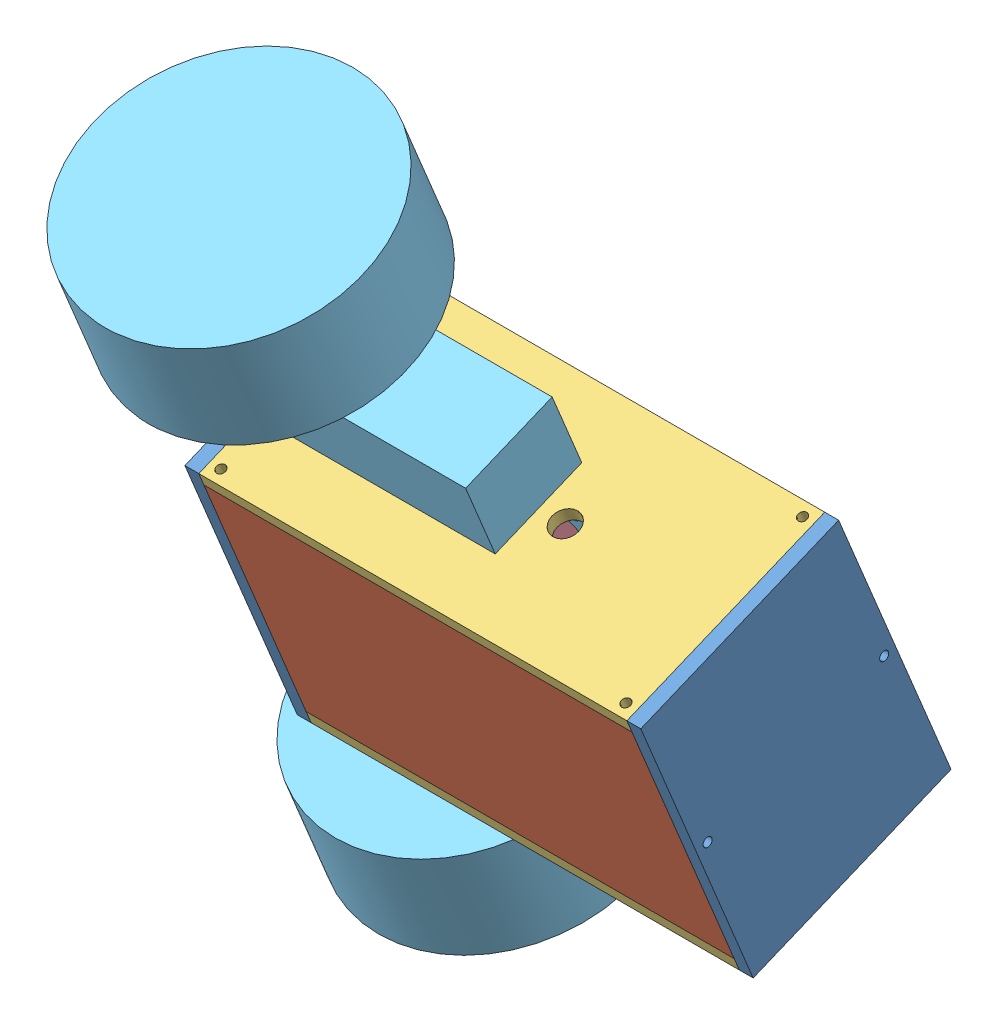
SolidWorks assembly Segway Assembly, configuration Default. Lengths in mm.
Overall size (133.86 181.3 123.57).
42 component instances, 24 part files, 24 mates.
Components (placement in the parent):
- Segway_Back-1: Segway_Back [Default] at (11.9402 18.0939 83.0712)
- Lid_Segway-3: Lid_Segway [Default] at (99.0068 121.3431 157.281) x (0 0.381849 -0.924225) z (-1 0 0) size (50.8 69.85 3.3)
- Lid_Segway-4: Lid_Segway [Default] at (203.9088 121.3431 157.281) x (0 0.381849 -0.924225) z (-1 0 0) size (50.8 69.85 3.3)
- Segway_Front-2: Segway_Front [Default] at (141.2112 46.7187 228.7497) x (1 0 0) z (0 0.924225 0.381849) size (101.6 3.17 63.5)
- Segway_side-3: Segway_side [Default] at (164.4936 84.3919 249.772) x (0 -0.381849 0.924225) z (0 0.924225 0.381849) size (50.8 101.6 3.17)
- Segway_side-4: Segway_side [Default] at (164.4936 22.7693 224.3122) x (0 -0.381849 0.924225) z (0 0.924225 0.381849) size (50.8 101.6 3.17)
- Segway_Back2-2: Segway_Back2 [Default] at (158.4024 66.1167 181.7991) x (-1 0 0) z (0 0.924225 0.381849) size (101.6 3.17 63.5)
- Final-1: Final [Predeterminado] at (194.5108 99.8085 199.1543) x (-1 0 0) z (0 0.924225 0.381849) size (74.75 15.43 53.34)
  - PCB_Final-1: PCB_Final [Default] at origin size (68.58 2 53.34)
  - Header Vertical 2.54mm Pitch2-1: Header Vertical 2.54mm Pitch2 [Header 6 Way] at (62.2731 2 -29.1415) size (5.08 8.88 7.62)
  - IC DIP 28-1: IC DIP 28 [Default] at (51.4233 4.3498 -16.4837) x (0 0.005002 0.999987) z (-1 0 0) size (7.87 6.22 35.94)
  - User Library-QFN32 (FTDI)-1: User Library-QFN32 (FTDI) [Default] at (19.2089 2.05 -38.1588) x (-1 0 0) z (0 1 0) size (5 5 0.85)
    - User Library-QFN32 (FTDI)_Anschl_X_FCsse_1-1: User Library-QFN32 (FTDI)_Anschl_X_FCsse_1 [Default] x (0 -1 0) z (0 0 1) size (5 5 0.2)
    - User Library-QFN32 (FTDI)_K_X_F6rper_1-1: User Library-QFN32 (FTDI)_K_X_F6rper_1 [Default] at origin size (5 5 0.8)
    - User Library-QFN32 (FTDI)_Beschriftung_1-1: User Library-QFN32 (FTDI)_Beschriftung_1 [Default] at origin size (0.51 0.51 0.05)
  - User Library-67068-0000-molex-1: User Library-67068-0000-molex [Default] at (-6.1546 2 -38.0545) x (0.002421 0 0.999997) z (-0.999997 0 0.002421) size (14.9 15.43 17)
  - User Library-dc range - dc connector[4840_2201]-1: User Library-dc range - dc connector[4840_2201] [Default] at (11.794 2 -12.8354) x (0 0 1) z (-1 0 0) size (9.51 14.5 13.83)
  - LED 1206-2: LED 1206 [Default] at (28.1068 2 -36.9237) x (0 0 -1) z (1 0 0) size (1.6 1.1 3.2)
  - LED 1206-3: LED 1206 [Default] at (28.142 2 -34.2868) x (0 0 -1) z (1 0 0) size (1.6 1.1 3.2)
  - LED 1206-4: LED 1206 [Default] at (58.3346 2 -36.8813) x (0 0 -1) z (1 0 0) size (1.6 1.1 3.2)
  - LED 1206-5: LED 1206 [Default] at (28.1068 2 -41.994) x (0 0 -1) z (1 0 0) size (1.6 1.1 3.2)
  - XTAL Small-1: XTAL Small [Default] at (14.2222 2 -30.4346) x (1 0 0) z (0 1 0) size (10.67 3.05 5.63)
  - Stackable Female Pin Header-1: Stackable Female Pin Header [6 Way] at (50.8347 2 -2.5872) size (15.24 8.3 2.54)
  - Stackable Female Pin Header-2: Stackable Female Pin Header [Default] at (45.7158 1.1368 -50.806) size (20.32 8.3 2.54)
  - Stackable Female Pin Header-3: Stackable Female Pin Header [Default] at (23.9415 1.1201 -50.7298) size (20.32 8.3 2.54)
  - Stackable Female Pin Header-4: Stackable Female Pin Header [6 Way] at (33.5006 2 -2.5872) size (15.24 8.3 2.54)
  - User Library-ALU-D8-1: User Library-ALU-D8 [Default] at (20.4464 1.8 -5.7935) x (0 0 -1) z (0 1 0) size (7 6.6 7.71)
    - User Library-ALU-D8_Pins_1-1: User Library-ALU-D8_Pins_1 [Default] at origin size (7 0.65 0.4)
    - User Library-ALU-D8_Fuss_1-1: User Library-ALU-D8_Fuss_1 [Default] at origin size (6.6 6.6 1)
    - User Library-ALU-D8_K_X_F6rper_1-1: User Library-ALU-D8_K_X_F6rper_1 [Default] at origin size (6.3 6.3 7)
    - User Library-ALU-D8_Beschriftung_1-1: User Library-ALU-D8_Beschriftung_1 [Default] at origin size (4.36 4.98 0.11)
  - User Library-ALU-D8-2: User Library-ALU-D8 [Default] at (28.1214 1.8 -5.7935) x (0 0 -1) z (0 1 0) size (7 6.6 7.71)
    - User Library-ALU-D8_Pins_1-1: User Library-ALU-D8_Pins_1 [Default] at origin size (7 0.65 0.4)
    - User Library-ALU-D8_Fuss_1-1: User Library-ALU-D8_Fuss_1 [Default] at origin size (6.6 6.6 1)
    - User Library-ALU-D8_K_X_F6rper_1-1: User Library-ALU-D8_K_X_F6rper_1 [Default] at origin size (6.3 6.3 7)
    - User Library-ALU-D8_Beschriftung_1-1: User Library-ALU-D8_Beschriftung_1 [Default] at origin size (4.36 4.98 0.11)
  - User Library-SOIC-8-1: User Library-SOIC-8 [Default] at (20.4108 1.85 -20.3024) x (0 0 -1) z (1 0 0) size (5 1.75 6.01)
    - User Library-SOIC-8_SOIC-8_Body_1-1: User Library-SOIC-8_SOIC-8_Body_1 [Default] at origin size (5 1.6 4)
    - User Library-SOIC-8_SOIC-8_Pins_1-1: User Library-SOIC-8_SOIC-8_Pins_1 [Default] at origin size (4.23 0.99 6.01)
  - SO 369A-1: SO 369A [Standard] at (5.5398 2 -17.4191) x (0 0 -1) z (0 1 0) size (6.6 10.1 2.4)
- Wheel-1: Wheel [Default] at (123.7191 42.6686 176.1481) x (0 0.381849 -0.924225) z (0 -0.924225 -0.381849) size (63.5 86.11 50.04)
- Wheel-2: Wheel [Default] at (123.7191 90.677 242.8745) x (0 -0.381849 0.924225) z (0 0.924225 0.381849) size (63.5 86.11 50.04)
Mates (geometry in assembly coordinates):
- Coincident7: coincident anti-aligned: plane of Segway_Front-2 through (99.0068 87.5303 242.1759) normal (0 0.924225 0.381849); plane of Segway_side-3 through (164.4936 84.3919 249.772) normal (0 -0.924225 -0.381849)
- Coincident8: coincident aligned: plane of Segway_Front-2 through (141.2112 46.7187 228.7497) normal (0 -0.381849 0.924225); plane of Segway_side-3 through (200.6068 89.2524 246.3227) normal (0 -0.381849 0.924225)
- Coincident9: coincident aligned: plane of Segway_Front-2 through (99.0068 28.8421 217.9285) normal (-1 0 0); plane of Segway_side-3 through (99.0068 108.6503 199.3721) normal (-1 0 0)
- Coincident10: coincident anti-aligned: plane of Segway_Front-2 through (99.0068 28.8421 217.9285) normal (0 -0.924225 -0.381849); plane of Segway_side-4 through (164.4936 25.7037 225.5246) normal (0 0.924225 0.381849)
- Coincident11: coincident aligned: plane of Segway_Front-2 through (99.0068 28.8421 217.9285) normal (-1 0 0); plane of Segway_side-4 through (99.0068 47.0276 173.9123) normal (-1 0 0)
- Coincident12: coincident aligned: plane of Segway_Front-2 through (141.2112 46.7187 228.7497) normal (0 -0.381849 0.924225); plane of Segway_side-4 through (200.6068 27.6297 220.8629) normal (0 -0.381849 0.924225)
- Coincident13: coincident anti-aligned: plane of Lid_Segway-4 through (200.6068 121.3431 157.281) normal (-1 0 0); plane of Segway_side-4 through (200.6068 47.0276 173.9123) normal (1 0 0)
- Coincident14: coincident aligned: plane of Lid_Segway-4 through (200.6068 24.6953 219.6505) normal (0 -0.924225 -0.381849); plane of Segway_side-4 through (164.4936 22.7693 224.3122) normal (0 -0.924225 -0.381849)
- Coincident15: coincident aligned: plane of Lid_Segway-4 through (200.6068 44.0932 172.6999) normal (0 0.381849 -0.924225); plane of Segway_side-4 through (200.6068 47.0276 173.9123) normal (0 0.381849 -0.924225)
- Coincident16: coincident anti-aligned: plane of Lid_Segway-3 through (99.0068 121.3431 157.281) normal (1 0 0); plane of Segway_Front-2 through (99.0068 28.8421 217.9285) normal (-1 0 0)
- Coincident17: coincident aligned: plane of Lid_Segway-3 through (95.7048 24.6953 219.6505) normal (0 -0.924225 -0.381849); plane of Segway_side-4 through (164.4936 22.7693 224.3122) normal (0 -0.924225 -0.381849)
- Coincident18: coincident aligned: plane of Lid_Segway-3 through (95.7048 44.0932 172.6999) normal (0 0.381849 -0.924225); plane of Segway_side-4 through (200.6068 47.0276 173.9123) normal (0 0.381849 -0.924225)
- Coincident31: coincident aligned: plane of Segway_side-3 through (200.6068 108.6503 199.3721) normal (0 0.381849 -0.924225); plane of Segway_Back2-2 through (158.4024 66.1167 181.7991) normal (0 0.381849 -0.924225)
- Coincident32: coincident anti-aligned: plane of Lid_Segway-3 through (99.0068 121.3431 157.281) normal (1 0 0); plane of Segway_Back2-2 through (99.0068 45.8153 176.8467) normal (-1 0 0)
- Coincident33: coincident anti-aligned: plane of Segway_side-3 through (164.4936 84.3919 249.772) normal (0 -0.924225 -0.381849); plane of Segway_Back2-2 through (200.6068 104.5035 201.0941) normal (0 0.924225 0.381849)
- Coincident34: coincident anti-aligned: plane of Segway_Back2-2 through (158.4024 64.9043 184.7335) normal (0 -0.381849 0.924225); plane of Final-1/PCB_Final-1 through (228.0951 75.1424 188.9634) normal (0 0.381849 -0.924225)
- Concentric7: concentric anti-aligned: cylinder of Segway_Back2-2 through (128.4708 68.1554 182.6414) axis (0 -0.381849 0.924225) radius 1.1976; cylinder of Final-1/PCB_Final-1 through (128.4708 66.1793 187.4242) axis (0 0.381849 -0.924225) radius 1.6
- Concentric8: concentric anti-aligned: cylinder of Segway_Back2-2 through (128.4708 93.9782 193.3102) axis (0 -0.381849 0.924225) radius 1.1976; cylinder of Final-1/PCB_Final-1 through (128.4708 92.0022 198.0931) axis (0 0.381849 -0.924225) radius 1.6
- Concentric9: concentric aligned: cylinder of Segway_side-4 through (124.4068 37.7161 188.1349) axis (0 0.924225 0.381849) radius 1.4605; cylinder of Wheel-1 through (124.4068 20.6965 181.1032) axis (0 0.924225 0.381849) radius 1.5875
- Concentric10: concentric aligned: cylinder of Segway_side-4 through (124.4068 31.0723 204.2155) axis (0 0.924225 0.381849) radius 1.4605; cylinder of Wheel-1 through (124.4068 14.0528 197.1838) axis (0 0.924225 0.381849) radius 1.5875
- Coincident38: coincident anti-aligned: plane of Segway_side-4 through (164.4936 22.7693 224.3122) normal (0 -0.924225 -0.381849); plane of Wheel-1 through (123.7191 42.6686 176.1481) normal (0 0.924225 0.381849)
- Concentric11: concentric anti-aligned: cylinder of Segway_side-3 through (124.4068 92.695 229.6753) axis (0 0.924225 0.381849) radius 1.4605; cylinder of Wheel-2 through (124.4068 112.649 237.9195) axis (0 -0.924225 -0.381849) radius 1.5875
- Concentric12: concentric anti-aligned: cylinder of Segway_side-3 through (124.4068 99.3388 213.5947) axis (0 0.924225 0.381849) radius 1.4605; cylinder of Wheel-2 through (124.4068 119.2928 221.8389) axis (0 -0.924225 -0.381849) radius 1.5875
- Coincident39: coincident anti-aligned: plane of Segway_side-3 through (164.4936 87.3263 250.9844) normal (0 0.924225 0.381849); plane of Wheel-2 through (123.7191 90.677 242.8745) normal (0 -0.924225 -0.381849)
